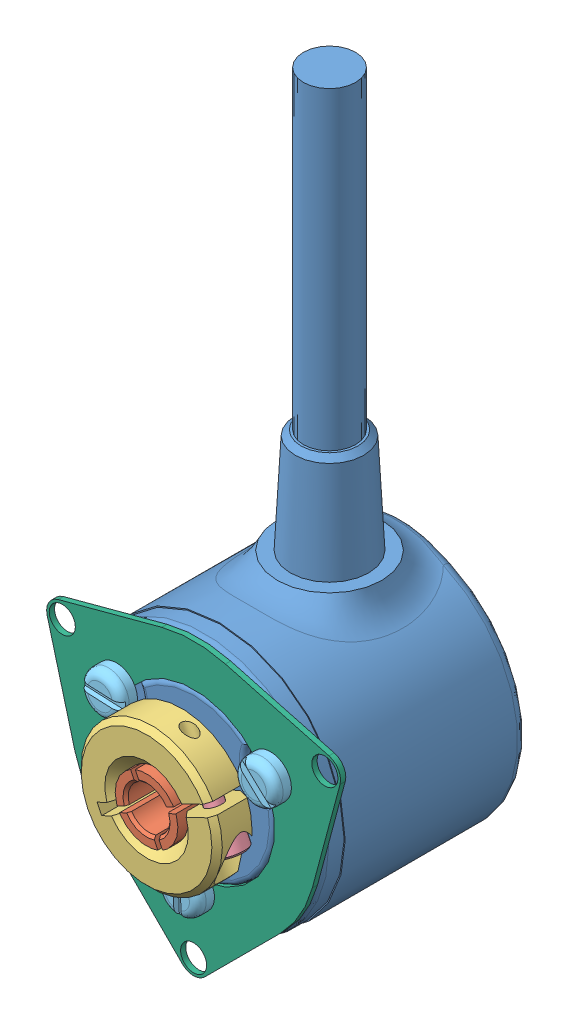
SolidWorks assembly Codeur_2MRH, configuration Default. Lengths in mm.
Overall size (38.09 70.8 24.5).
8 component instances, 6 part files, 16 mates.
Components (placement in the parent):
- corps_codeur_2MRH-1: corps_codeur_2MRH [Default] at (3.2886 -2.5929 -14.3048) size (24 64.75 20.04)
- mandrin_codeur_2MRH-1: mandrin_codeur_2MRH [Default] at (3.2886 -2.5929 -3.8048) x (-0.434638 0.900605 0) z (0 0 1) size (6 6 14)
- bague_codeur_2MRH-1: bague_codeur_2MRH [Default] at (3.2886 -2.5929 5.6952) x (0.434638 -0.900605 0) z (0 0 1) size (13.5 13.48 4.5)
- Vis_CHC_M2_L5-1: Vis_CHC_M2_L5 [B18.3.1M - 1.6 x 0.35 x 5 Hex SHCS -- 5NHX] at (9.1066 -4.3376 7.9452) x (-0.434638 0.900605 0) z (0 0 1) size (6.6 3 3)
- Vis_fendue_tete_bombee_M2_L5-1: Vis_fendue_tete_bombee_M2_L5 [B18.6.7M - M2 x 0.4 x 4 Slotted PHMS --4N] at (10.6498 1.6571 7.2952) x (0 0 -1) z (0.728333 -0.685223 0) size (5.65 4 4)
- Vis_fendue_tete_bombee_M2_L5-2: Vis_fendue_tete_bombee_M2_L5 [B18.6.7M - M2 x 0.4 x 4 Slotted PHMS --4N] at (-4.0726 1.6571 7.2952) x (0 0 -1) z (0.998972 -0.045336 0) size (5.65 4 4)
- Vis_fendue_tete_bombee_M2_L5-3: Vis_fendue_tete_bombee_M2_L5 [B18.6.7M - M2 x 0.4 x 4 Slotted PHMS --4N] at (3.2886 -11.0929 7.2952) x (0 0 -1) z (-0.043781 0.999041 0) size (5.65 4 4)
- Bride_membrane-1: Bride_membrane [Default] at (3.2886 -2.5929 5.6952) x (0.5 0.866025 0) z (-0.866025 0.5 0) size (28.11 0.5 27.75)
Mates (geometry in assembly coordinates):
- Coaxiale2: concentric anti-aligned: cylinder of corps_codeur_2MRH-1 through (3.2886 -2.5929 -3.8048) axis (0 0 1) radius 3; cylinder of mandrin_codeur_2MRH-1 through (3.2886 -2.5929 10.1952) axis (0 0 -1) radius 3
- Coïncidente1: coincident anti-aligned: plane of corps_codeur_2MRH-1 through (3.2886 -2.5929 -3.8048) normal (0 0 1); plane of mandrin_codeur_2MRH-1 through (3.2886 -2.5929 -3.8048) normal (0 0 -1)
- Coïncidente2: coincident anti-aligned: plane of corps_codeur_2MRH-1 through (3.2886 -2.5929 5.6952) normal (0 0 1); plane of bague_codeur_2MRH-1 through (3.2886 -2.5929 5.6952) normal (0 0 -1)
- Coaxiale3: concentric aligned: cylinder of mandrin_codeur_2MRH-1 through (3.2886 -2.5929 10.1952) axis (0 0 -1) radius 3; cylinder of bague_codeur_2MRH-1 through (3.2886 -2.5929 10.1952) axis (0 0 -1) radius 3
- Parallèle1: parallel aligned: plane of mandrin_codeur_2MRH-1 through (3.4051 -2.2591 0.1952) normal (0.434638 -0.900605 0); plane of bague_codeur_2MRH-1 through (9.1337 0.7831 5.6942) normal (0.434638 -0.900605 0)
- Coaxiale41: concentric anti-aligned: cylinder of bague_codeur_2MRH-1 through (8.4112 -2.8966 7.9452) axis (-0.434638 0.900605 0) radius 0.75; cylinder of Vis_CHC_M2_L5-1 through (22.9064 -32.9318 7.9452) axis (0.434638 -0.900605 0) radius 1.5
- Coïncidente41: coincident anti-aligned: plane of bague_codeur_2MRH-1 through (8.4112 -2.8966 7.9452) normal (0.434638 -0.900605 0); plane of Vis_CHC_M2_L5-1 through (7.0603 -3.5486 7.9452) normal (-0.434638 0.900605 0)
- Coaxiale81: concentric aligned: cylinder of corps_codeur_2MRH-1 through (10.6498 1.6571 5.1952) axis (0 0 1) radius 0.8; cylinder of Vis_fendue_tete_bombee_M2_L5-1 through (10.6498 1.6571 32.6952) axis (0 0 1) radius 2
- Coaxiale91: concentric aligned: cylinder of corps_codeur_2MRH-1 through (-4.0726 1.6571 5.1952) axis (0 0 1) radius 0.8; cylinder of Vis_fendue_tete_bombee_M2_L5-2 through (-4.0726 1.6571 32.6952) axis (0 0 1) radius 2
- Coaxiale101: concentric aligned: cylinder of corps_codeur_2MRH-1 through (3.2886 -11.0929 5.1952) axis (0 0 1) radius 0.8; cylinder of Vis_fendue_tete_bombee_M2_L5-3 through (3.2886 -11.0929 32.6952) axis (0 0 1) radius 2
- Coïncidente102: coincident anti-aligned: plane of corps_codeur_2MRH-1 through (3.2886 -2.5929 5.1952) normal (0 0 1); plane of Bride_membrane-1 through (3.2886 -2.5929 5.1952) normal (0 0 -1)
- Coïncidente103: coincident aligned: circle of corps_codeur_2MRH-1; cylinder of Bride_membrane-1 through (3.2886 -2.5929 5.1952) axis (0 0 1) radius 7.75
- Coaxiale102: concentric aligned: cylinder of corps_codeur_2MRH-1 through (-4.0726 1.6571 5.1952) axis (0 0 1) radius 0.8; cylinder of Bride_membrane-1 through (-4.0726 1.6571 5.1952) axis (0 0 1) radius 1.5
- Coïncidente104: coincident anti-aligned: plane of Vis_fendue_tete_bombee_M2_L5-2 through (-4.0273 2.6561 5.6952) normal (0 0 -1); plane of Bride_membrane-1 through (3.2886 -2.5929 5.6952) normal (0 0 1)
- Coïncidente105: coincident anti-aligned: plane of Vis_fendue_tete_bombee_M2_L5-1 through (11.335 2.3854 5.6952) normal (0 0 -1); plane of Bride_membrane-1 through (3.2886 -2.5929 5.6952) normal (0 0 1)
- Coïncidente106: coincident anti-aligned: plane of Vis_fendue_tete_bombee_M2_L5-3 through (2.2896 -11.1367 5.6952) normal (0 0 -1); plane of Bride_membrane-1 through (3.2886 -2.5929 5.6952) normal (0 0 1)
